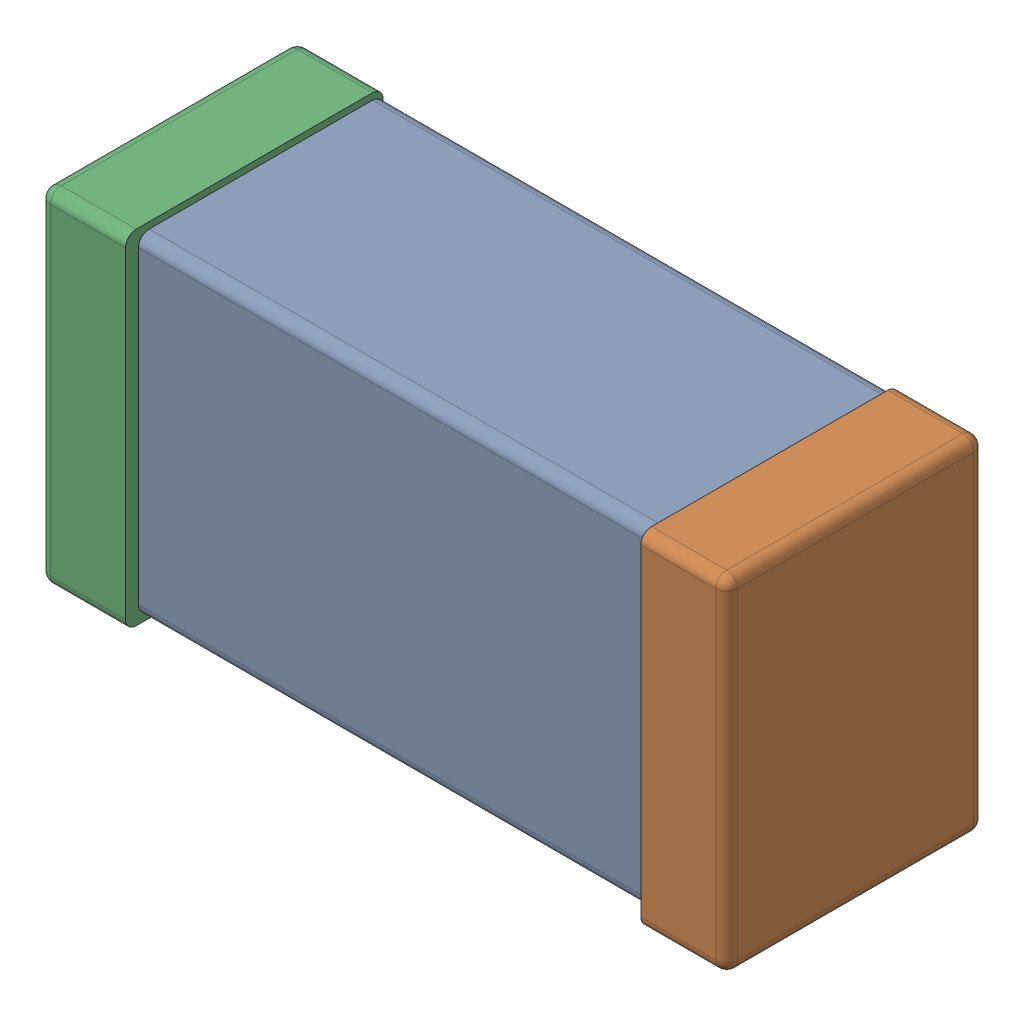
SolidWorks assembly C0603_060_5, configuration Standard. Lengths in mm.
Overall size (1.6 0.8 0.6).
3 component instances, 3 part files, 0 mates.
Components (placement in the parent):
- Part 3_1-1: Part 3_1 [Standard] at (0 0 -23.815) size (1.4 0.77 0.57)
- Part 2_1-1: Part 2_1 [Standard] at (0 0 -23.8) size (0.2 0.8 0.6)
- Part 1_1-1: Part 1_1 [Standard] at (0 0 -23.8) size (0.2 0.8 0.6)
